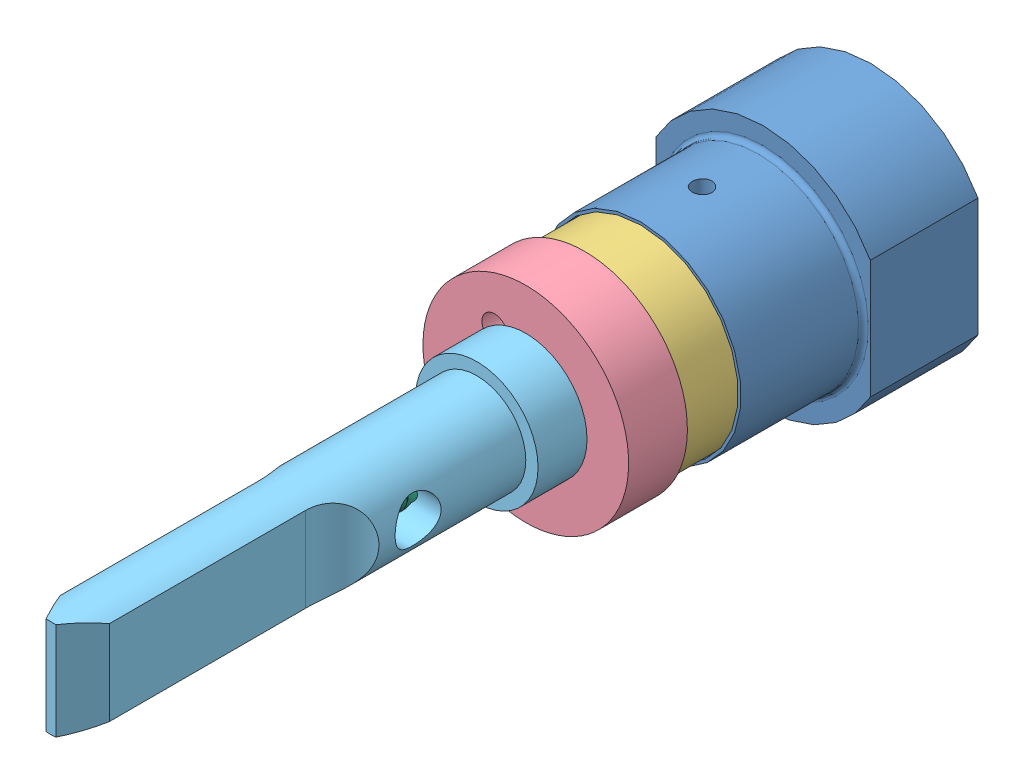
SolidWorks assembly D0902418-v2_aLIGO_SUS_HSTS_Magnet and Flag Assembly (Long), Upper Mass, configuration Default. Lengths in mm.
Overall size (14.71 14.71 42.54).
6 component instances, 6 part files, 10 mates.
Components (placement in the parent):
- D0902423_AdvLIGO_SUS_HSTS_Magnet Holder (Long), Upper Mass-1: D0902423_AdvLIGO_SUS_HSTS_Magnet Holder (Long), Upper Mass [Default] at (0 -12.2704 0) x (0 1 0) z (0 0 1) size (12.7 11.11 11.94)
- D1001534-v1_aLIGO_SUS_Magnetic Plug, SUS-1: D1001534-v1_aLIGO_SUS_Magnetic Plug, SUS [Default] at (0 -12.2704 9.938) x (1 0 0) z (0 -1 0) size (10.11 1 10.11)
- Magnet,_MMG_MagDev_DCNI_00626N-1: Magnet,_MMG_MagDev_DCNI_00626N [Default] at (0 -12.2704 10.938) x (-0.921004 0.389553 0) z (0 0 1) size (10 10 5)
- D1100574-1: D1100574 [Default] at (0 -12.2704 17.9038) x (-0.847203 -0.531269 0) z (0.531269 -0.847203 0) size (10.67 3.05 10.67)
- D1100573-1: D1100573 [Default] at (0 -12.2704 17.9038) x (0 -1 0) z (-1 0 0) size (6.35 24.64 6.35)
- 94518A108-1: 94518A108 [94518A108] at (0 -12.2704 25.463) x (0.448594 -0.893735 0) z (0 0 1) size (6.48 6.48 10.08)
Mates (geometry in assembly coordinates):
- Coincident13: coincident anti-aligned: plane of D1001534-v1_aLIGO_SUS_Magnetic Plug, SUS-1 through (0 -12.2704 10.938) normal (0 0 1); plane of Magnet,_MMG_MagDev_DCNI_00626N-1 through (0 -12.2704 10.938) normal (0 0 -1)
- Concentric10: concentric anti-aligned: cylinder of D0902423_AdvLIGO_SUS_HSTS_Magnet Holder (Long), Upper Mass-1 through (0 -12.2704 9.938) axis (0 0 1) radius 5.0546; cylinder of D1001534-v1_aLIGO_SUS_Magnetic Plug, SUS-1 through (0 -12.2704 10.938) axis (0 0 -1) radius 5.0546
- Coincident16: coincident anti-aligned: plane of D0902423_AdvLIGO_SUS_HSTS_Magnet Holder (Long), Upper Mass-1 through (0 -12.2704 9.938) normal (0 0 1); plane of D1001534-v1_aLIGO_SUS_Magnetic Plug, SUS-1 through (0 -12.2704 9.938) normal (0 0 -1)
- Concentric11: concentric anti-aligned: cylinder of D0902423_AdvLIGO_SUS_HSTS_Magnet Holder (Long), Upper Mass-1 through (0 -12.2704 9.938) axis (0 0 1) radius 5.0546; cylinder of Magnet,_MMG_MagDev_DCNI_00626N-1 through (0 -12.2704 15.938) axis (0 0 -1) radius 5
- Concentric12: concentric anti-aligned: circle of D1100574-1; cylinder of D1100573-1 through (0 -12.2704 17.9038) axis (0 0 -1) radius 1.1303
- Concentric13: concentric anti-aligned: cylinder of Magnet,_MMG_MagDev_DCNI_00626N-1 through (0 -12.2704 15.938) axis (0 0 -1) radius 5; cylinder of D1100574-1 through (0 -12.2704 17.9038) axis (0 0 1) radius 5.08
- Parallel1: parallel aligned: plane of D0902423_AdvLIGO_SUS_HSTS_Magnet Holder (Long), Upper Mass-1 through (5.5563 -9.1962 11.938) normal (1 0 0); plane of D1100573-1 through (1.27 -9.0954 42.5418) normal (1 0 0)
- Coincident19: coincident aligned: cone of D1100574-1 through (0 -12.2704 16.3798) axis (0 0 1); cone of 94518A108-1 through (0 -12.2704 16.0145) axis (0 0 1)
- Coincident20: coincident anti-aligned: plane of Magnet,_MMG_MagDev_DCNI_00626N-1 through (0 -12.2704 15.938) normal (0 0 1); plane of 94518A108-1 through (0 -12.2704 15.938) normal (0 0 -1)
- Coincident21: coincident anti-aligned: plane of D1100574-1 through (-1.3523 -13.1184 17.9038) normal (0 0 1); plane of D1100573-1 through (0 -12.2704 17.9038) normal (0 0 -1)
